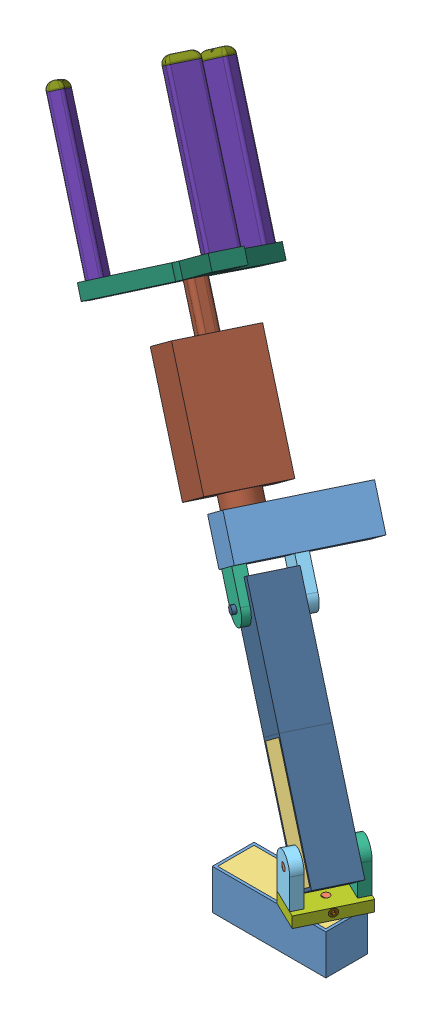
SolidWorks assembly 4DOFArm, configuration Default. Lengths in mm.
Overall size (483.83 648.12 331.1).
61 component instances, 18 part files, 13 mates.
Components (placement in the parent):
- Case1WithBearings-2: Case1WithBearings [Default] at (15.7322 41.1423 -46.3275) size (125 56 46)
  - Motor1WithCase-1: Motor1WithCase [Default] at (-7.1067 -6.2049 -11.0572) size (125 56 46)
    - ArmBase-1: ArmBase [Default] at (40.6555 43.6092 113.8063) size (125 44 46)
    - WormGearMotor-2: WormGearMotor [Default] at (-17.0445 63.1092 113.8063) x (0 0 -1) z (0 -1 0) size (40 117.2 52)
    - ArmBaseCover-2: ArmBaseCover [Default] at (40.6555 87.6092 113.8063) x (-1 0 0) z (0 0 1) size (119 4.5 40)
  - SB608ZZ-1: SB608ZZ [Default] at (73.0487 85.4044 102.7492) x (0 -1 0) z (0 0 1) size (7 22 22)
- ConnectingJoint-2: ConnectingJoint [Default] at (80.9509 127.6243 42.6354) x (0.900383 0 0.435099) z (-0.435099 0 0.900383) size (36 60 68.86)
  - BearingJoints-1: BearingJoints [Default] at (10.0484 39.9223 31.0061) size (30 48 12)
  - BearingJoints2-1: BearingJoints2 [Default] at (10.0484 39.9223 -12.9939) x (-1 0 0) z (0 0 -1) size (30 48 12)
  - JointBottom-1: JointBottom [Default] at (13.0484 -5.0777 9.0061) x (0 0 -1) z (1 0 0) size (68 12 36)
  - socket head cap screw_iso-1: socket head cap screw_iso [ISO 4762 M6 x 20 - 20S] at (3.0484 -5.0777 -18.9939) x (0 1 0) z (-0.488199 0 0.872732) size (26 10 10)
  - socket head cap screw_iso-2: socket head cap screw_iso [ISO 4762 M6 x 20 - 20S] at (3.0484 -5.0777 37.0061) x (0 1 0) z (0 0 1) size (26 10 10)
  - socket head cap screw_iso-3: socket head cap screw_iso [ISO 4762 M6 x 20 - 20S] at (17.0484 -5.0777 37.0061) x (0 1 0) z (0 0 1) size (26 10 10)
  - socket head cap screw_iso-4: socket head cap screw_iso [ISO 4762 M6 x 20 - 20S] at (17.0484 -5.0777 -18.9939) x (0 1 0) z (-0.513591 0 0.858035) size (26 10 10)
  - M5X10-1: M5X10 [Default] at (22.2578 2.0842 9.2195) x (-1 0 0) z (0 -0.924225 -0.381849) size (15 8.5 8.5)
- Motor2WithCase-1: Motor2WithCase [Default] at (114.1411 353.7501 64.0089) x (0.373772 -0.692879 0.616614) z (-0.015437 -0.669353 -0.742784) size (139.16 102.77 112.77)
  - WormGearMotor-2: WormGearMotor [Default] at (22.8097 94.5076 102.0809) x (0.052143 -0.73415 -0.676982) z (-0.392561 -0.6384 0.662074) size (40 117.2 52)
  - ArmBaseCover-2: ArmBaseCover [Default] at (85.4103 96.8062 104.4099) x (-0.918247 0.231235 -0.321487) z (-0.052143 0.73415 0.676982) size (119 4.5 40)
  - ArmBase2-1: ArmBase2 [Default] at (68.1376 68.7166 133.5411) x (0.918247 -0.231235 0.321487) z (-0.052143 0.73415 0.676982) size (125 56 46)
- Motor2WithCase-2: Motor2WithCase [Default] at (140.4502 310.9487 86.058) x (-0.299647 0.756895 -0.580794) z (-0.946941 -0.161774 0.277727) size (139.16 102.77 112.77)
  - WormGearMotor-2: WormGearMotor [Default] at (22.8097 94.5076 102.0809) x (0.052143 -0.73415 -0.676982) z (-0.392561 -0.6384 0.662074) size (40 117.2 52)
  - ArmBaseCover-2: ArmBaseCover [Default] at (85.4103 96.8062 104.4099) x (-0.918247 0.231235 -0.321487) z (-0.052143 0.73415 0.676982) size (119 4.5 40)
  - ArmBase2-1: ArmBase2 [Default] at (68.1376 68.7166 133.5411) x (0.918247 -0.231235 0.321487) z (-0.052143 0.73415 0.676982) size (125 56 46)
- WristJoint-1: WristJoint [Default] at (-161.7568 405.1622 56.3064) x (0.71016 0.614738 0.343176) z (0.435099 0 -0.900383) size (46 104 125)
  - ConnectingJoint2-1: ConnectingJoint2 [Default] at (19.8862 87.6652 94.835) size (46 92 125)
    - BearingJoints-1: BearingJoints [Default] at (9.8682 32.6089 36.0698) size (30 48 12)
    - BearingJoints2-1: BearingJoints2 [Default] at (9.8682 32.6089 -3.9302) x (-1 0 0) z (0 0 -1) size (30 48 12)
    - ArmBase-1: ArmBase [Default] at (9.8682 -0.3911 46.5698) x (0 0 -1) z (-1 0 0) size (125 44 46)
  - WormGearMotor-1: WormGearMotor [Default] at (29.7544 67.7741 199.1048) x (1 0 0) z (0 1 0) size (40 117.2 52)
  - ArmBaseCover-1: ArmBaseCover [Default] at (29.7544 43.2741 141.4048) x (0 0 1) z (-1 0 0) size (119 4.5 40)
  - SB608ZZ-1: SB608ZZ [Default] at (29.7544 120.2741 86.9048) x (0 0 1) z (-1 0 0) size (7 22 22)
  - SB608ZZ-2: SB608ZZ [Default] at (29.7544 120.2741 127.9048) x (0 0 1) z (-0.001374 0.999999 0) size (7 22 22)
  - SB608ZZ-3: SB608ZZ [Default] at (29.7544 39.2741 101.9048) x (0 1 0) z (0 0 1) size (7 22 22)
- GrapperWithServos-1: GrapperWithServos [Default] at (-93.8919 541.249 -49.8434) x (-0.406954 0.024074 0.913131) z (0.553499 -0.788732 0.267472) size (170.88 147.99 355)
  - ServoHolder-1: ServoHolder [Default] at (20.6091 41.5283 66.4389) size (76 55.75 187)
  - ServoWithHornCover-1: ServoWithHornCover [Default] at (-47.2507 32.9202 59.0729) x (0 0 -1) z (1 0 0) size (60.01 49.75 41.52) (flexible)
    - MG996R-1: MG996R [Default] at (22.884 11.6081 50.6098) size (53.5 42.75 19.5)
    - ServoHornWithGroove-1: ServoHornWithGroove [Default] at (12.384 56.3581 50.6098) x (0.653288 0 0.75711) z (0.75711 0 -0.653288) size (30 9.5 30)
    - ServoCover-1: ServoCover [Default] at (34.0772 41.3581 67.8598) x (-1 0 0) z (0 0 -1) size (57.5 20 34.5)
  - ServoWithHornCover-2: ServoWithHornCover [Default] at (-12.7507 32.9202 59.0729) x (0 0 -1) z (1 0 0) size (60.01 49.75 41.52) (flexible)
    - MG996R-1: MG996R [Default] at (22.884 11.6081 50.6098) size (53.5 42.75 19.5)
    - ServoHornWithGroove-1: ServoHornWithGroove [Default] at (12.384 56.3581 50.6098) x (0.586538 0 0.809922) z (0.809922 0 -0.586538) size (30 9.5 30)
    - ServoCover-1: ServoCover [Default] at (34.0772 41.3581 67.8598) x (-1 0 0) z (0 0 -1) size (57.5 20 34.5)
  - 3GripperAssembly-1: 3GripperAssembly [Default] at (-30.3334 -49.3942 19.9719) x (1 0 0) z (0 1 0) size (170.88 173 147.99)
    - EndEffector3Grapper-1: EndEffector3Grapper [Default] at (50.9425 60.533 115.9226) size (170.88 20 147.99)
    - FingerAssembly-1: FingerAssembly [Default] at (105.0348 198.5242 138.6511) x (-0.5 0 0.866025) z (0 1 0) size (30 15 158)
      - FingerTip-1: FingerTip [Default] at (7.3627 17.1904 24.0088) size (30 15 11)
      - Finger-1: Finger [Default] at (7.3627 18.2904 -122.9912) x (1 0 0) z (0 -1 0) size (30 150 15)
    - FingerAssembly-2: FingerAssembly [Default] at (4.2129 198.5242 151.4036) x (-0.5 0 -0.866025) z (0 1 0) size (30 15 158)
      - FingerTip-1: FingerTip [Default] at (7.3627 17.1904 24.0088) size (30 15 11)
      - Finger-1: Finger [Default] at (7.3627 18.2904 -122.9912) x (1 0 0) z (0 -1 0) size (30 150 15)
    - FingerAssembly-3: FingerAssembly [Default] at (43.5799 198.5242 57.713) x (1 0 0) z (0 1 0) size (30 15 158)
      - FingerTip-1: FingerTip [Default] at (7.3627 17.1904 24.0088) size (30 15 11)
      - Finger-1: Finger [Default] at (7.3627 18.2904 -122.9912) x (1 0 0) z (0 -1 0) size (30 150 15)
  - ServoWithHornCover-4: ServoWithHornCover [Default] at (-30.0007 32.9202 119.5729) x (0 0 -1) z (1 0 0) size (60.01 49.75 41.52)
    - MG996R-1: MG996R [Default] at (22.884 11.6081 50.6098) size (53.5 42.75 19.5)
    - ServoHornWithGroove-1: ServoHornWithGroove [Default] at (12.384 56.3581 50.6098) x (-0.837169 0 -0.546944) z (-0.546944 0 0.837169) size (30 9.5 30)
    - ServoCover-1: ServoCover [Default] at (34.0772 41.3581 67.8598) x (-1 0 0) z (0 0 -1) size (57.5 20 34.5)
  - ServoHolderCover-1: ServoHolderCover [Default] at (20.6091 94.2783 66.4389) x (0 0 -1) z (1 0 0) size (118 3 70)
  - socket head cap screw_iso-1: socket head cap screw_iso [ISO 4762 M6 x 20 - 20S] at (20.6091 66.5283 -55.5611) x (0 0 1) z (-0.923728 -0.383049 0) size (26 10 10)
- M5X10-1: M5X10 [Default] at (-83.7779 390.3129 -18.5489) x (0.726655 0.614266 0.307652) z (-0.658148 0.750853 0.055332) size (15 8.5 8.5)
Mates (geometry in assembly coordinates):
- Concentric4: concentric aligned: cylinder of Case1WithBearings-2/SB608ZZ-1 through (88.7809 119.8466 56.4217) axis (0 -1 0) radius 11; cylinder of ConnectingJoint-2/JointBottom-1 through (88.7809 126.5466 56.4217) axis (0 -1 0) radius 11
- Coincident4: coincident anti-aligned: plane of Case1WithBearings-2/SB608ZZ-1 through (99.4809 126.5466 56.4217) normal (0 1 0); plane of ConnectingJoint-2/JointBottom-1 through (88.7809 126.5466 56.4217) normal (0 -1 0)
- Concentric5: concentric anti-aligned: cylinder of ConnectingJoint-2/BearingJoints-1 through (74.7672 167.5466 78.5263) axis (0.435099 0 -0.900383) radius 11; cylinder of Motor2WithCase-1/WormGearMotor-2 through (79.9884 167.5466 67.7217) axis (-0.435099 0 0.900383) radius 4
- Coincident5: coincident anti-aligned: plane of ConnectingJoint-2/BearingJoints-1 through (76.5076 167.5466 74.9248) normal (0.435099 0 -0.900383); plane of Motor2WithCase-1/ArmBaseCover-2 through (54.676 198.7289 64.375) normal (-0.435099 0 0.900383)
- Coincident6: coincident aligned: plane of Motor2WithCase-1/ArmBase2-1 through (3.7844 233.9495 39.7823) normal (-0.710785 -0.613847 -0.343478); plane of Motor2WithCase-2/ArmBase2-1 through (22.9288 233.9495 0.1654) normal (-0.710785 -0.613847 -0.343478)
- Coincident7: coincident aligned: plane of Motor2WithCase-1/ArmBaseCover-2 through (54.676 198.7289 64.375) normal (-0.435099 0 0.900383); plane of Motor2WithCase-2/ArmBase2-1 through (-14.4111 297.4071 30.9895) normal (-0.435099 0 0.900383)
- Coincident8: coincident anti-aligned: plane of Motor2WithCase-1/ArmBase2-1 through (3.7844 233.9495 39.7823) normal (-0.552697 0.789425 -0.267084); plane of Motor2WithCase-2/ArmBase2-1 through (22.9288 233.9495 0.1654) normal (0.552697 -0.789425 0.267084)
- Concentric9: concentric anti-aligned: cylinder of Motor2WithCase-2/WormGearMotor-2 through (-20.5791 328.5894 -11.9741) axis (0.435099 0 -0.900383) radius 4; cylinder of WristJoint-1/ConnectingJoint2-1/BearingJoints-1 through (-11.8771 328.5894 -29.9817) axis (-0.435099 0 0.900383) radius 4
- Coincident11: coincident anti-aligned: plane of Motor2WithCase-2/WormGearMotor-2 through (-18.4036 328.5894 -16.476) normal (0.435099 0 -0.900383); plane of WristJoint-1/SB608ZZ-2 through (-10.7967 335.1555 -12.8001) normal (-0.435099 0 0.900383)
- Concentric10: concentric aligned: cylinder of WristJoint-1/SB608ZZ-3 through (-70.8412 387.1921 -12.9392) axis (0.553499 -0.788732 0.267472) radius 11; cylinder of GrapperWithServos-1/ServoHolder-1 through (-74.5496 392.4766 -14.7312) axis (0.553499 -0.788732 0.267472) radius 11
- Coincident12: coincident anti-aligned: plane of WristJoint-1/SB608ZZ-3 through (-82.1483 385.8989 -18.4032) normal (-0.553499 0.788732 -0.267472); plane of GrapperWithServos-1/ServoHolder-1 through (-74.5496 392.4766 -14.7312) normal (0.553499 -0.788732 0.267472)
- Concentric11: concentric aligned: cylinder of GrapperWithServos-1/ServoHolder-1 through (-86.4869 388.0404 -19.9343) axis (-0.726655 -0.614266 -0.307652) radius 4.25; cylinder of M5X10-1 through (-86.4869 388.0404 -19.9343) axis (-0.726655 -0.614266 -0.307652) radius 4.25
- Coincident14: coincident anti-aligned: plane of GrapperWithServos-1/ServoHolder-1 through (-86.4869 388.0404 -19.9343) normal (-0.726655 -0.614266 -0.307652); plane of M5X10-1 through (-85.6495 389.0719 -23.9714) normal (0.726655 0.614266 0.307652)
